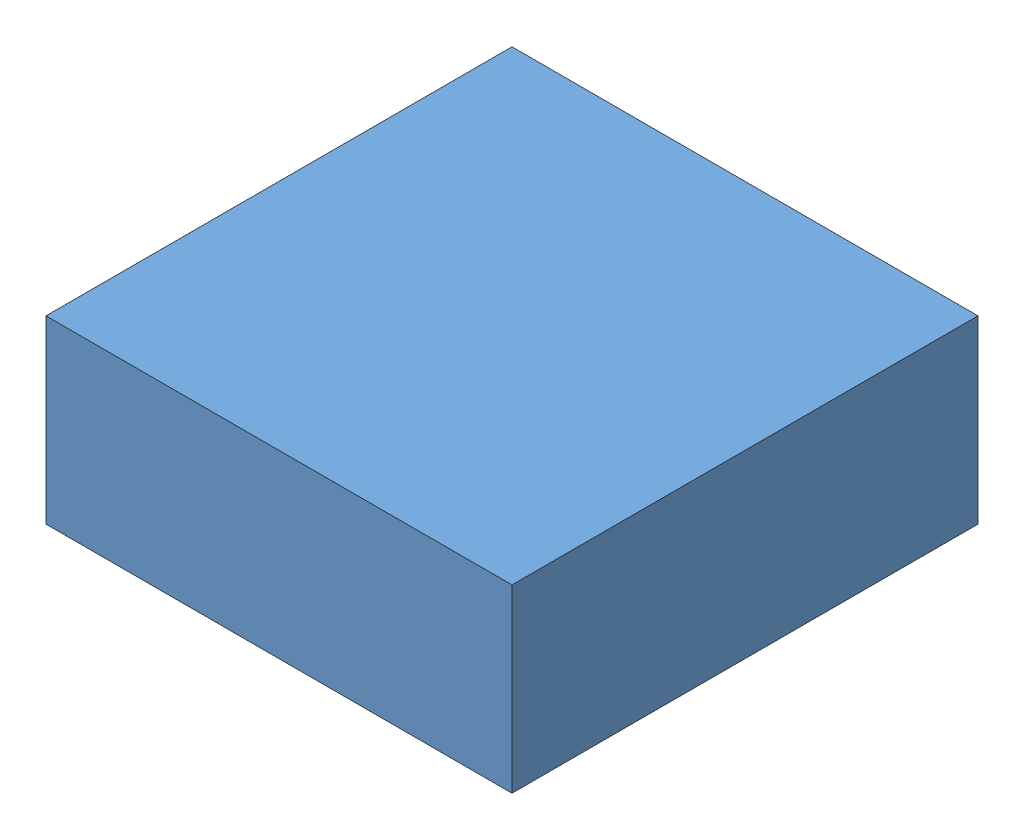
SolidWorks assembly Inverse Perfusion Cap Assembly, configuration Default. Lengths in mm.
Overall size (31 12 31).
2 component instances, 2 part files, 1 mates.
Components (placement in the parent):
- Cavity-2: Cavity [Default] at (4.0861 -23.0191 25.891) size (31 12 31)
- Inverted Perfusion Cap Nozzles v9-2: Inverted Perfusion Cap Nozzles v9 [Default] at (3.8664 -21.0191 25.9073) size (27 8 27)
Mates (geometry in assembly coordinates):
- Coincident1: coincident aligned: plane of Cavity-2 through (4.0861 -23.0191 25.891) normal (0 -1 0); plane of Inverted Perfusion Cap Nozzles v9-2 through (3.8664 -23.0191 25.9073) normal (0 -1 0)
